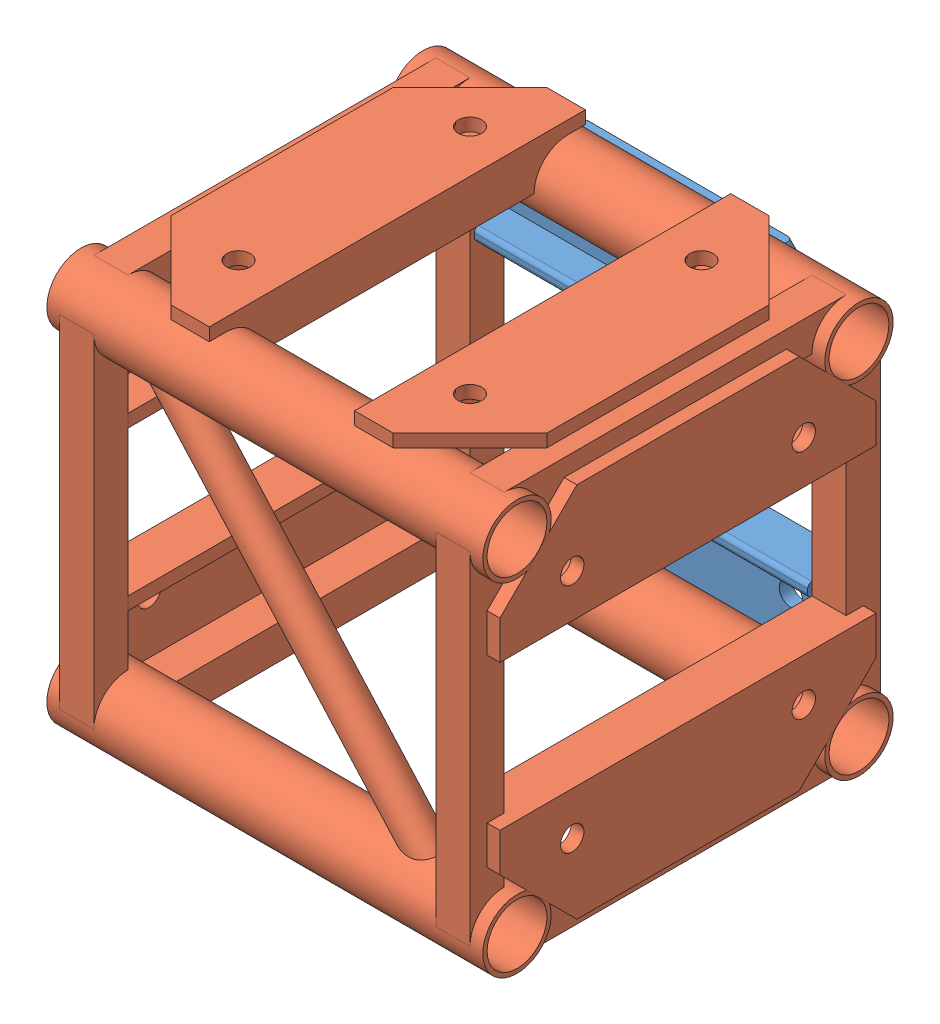
SolidWorks assembly FE-01013, configuration Default. Lengths in mm.
Overall size (323.85 314.33 314.32).
3 component instances, 2 part files, 6 mates.
Components (placement in the parent):
- Connection Plate _ TS Standard-1: Connection Plate _ TS Standard [Default] at (-13576.8315 -2429.2002 3196.1374) size (273.05 85.72 34.92)
- Connection Plate _ TS Standard-2: Connection Plate _ TS Standard [Default] at (-13576.8315 -2247.7172 3196.1374) x (-1 0 0) z (0 0 1) size (273.05 85.72 34.92)
- FE-01013-01-1: FE-01013-01 [Default] at (-13576.8315 -2333.6962 3340.5999) size (323.85 314.33 304.8)
Mates (geometry in assembly coordinates):
- Coincident1: coincident anti-aligned: plane of FE-01013-01-1 through (-13729.2315 -2211.4587 3188.1999) normal (0 0 -1); plane of Connection Plate _ TS Standard-2 through (-13576.8315 -2247.7172 3188.1999) normal (0 0 1)
- Coincident2: coincident anti-aligned: plane of FE-01013-01-1 through (-13424.4315 -2211.4587 3188.1999) normal (0 0 -1); plane of Connection Plate _ TS Standard-1 through (-13576.8315 -2429.2002 3188.1999) normal (0 0 1)
- Width1: width anti-aligned: plane of FE-01013-01-1 through (-13424.4315 -2211.4587 3213.5999) normal (1 0 0); plane of Connection Plate _ TS Standard-2 through (-13729.2315 -2211.4587 3213.5999) normal (-1 0 0); plane of FE-01013-01-1 through (-13700.6565 -2290.5797 3213.5999) normal (-1 0 0); plane of Connection Plate _ TS Standard-2 through (-13453.0065 -2281.0547 3213.5999) normal (1 0 0)
- Width2: width anti-aligned: plane of Connection Plate _ TS Standard-1 through (-13700.6565 -2395.8627 3213.5999) normal (-1 0 0); plane of FE-01013-01-1 through (-13453.0065 -2386.3377 3213.5999) normal (1 0 0); plane of Connection Plate _ TS Standard-1 through (-13424.4315 -2211.4587 3213.5999) normal (1 0 0); plane of FE-01013-01-1 through (-13729.2315 -2211.4587 3213.5999) normal (-1 0 0)
- Distance1: distance = 171.958 mm: cylinder of Connection Plate _ TS Standard-1 through (-13490.8525 -2424.4377 3178.6749) axis (0 0 -1) radius 8.7312; cylinder of Connection Plate _ TS Standard-2 through (-13490.8525 -2252.4797 3178.6749) axis (0 0 -1) radius 8.7312
- Width3: width anti-aligned: plane of FE-01013-01-1 through (-13424.4315 -2186.0587 3467.5999) normal (0 1 0); plane of FE-01013-01-1 through (-13424.4315 -2490.8587 3213.5999) normal (0 -1 0); plane of Connection Plate _ TS Standard-1 through (-13654.619 -2472.0627 3178.6749) normal (0 -1 0); plane of Connection Plate _ TS Standard-2 through (-13499.044 -2204.8547 3178.6749) normal (0 1 0)
